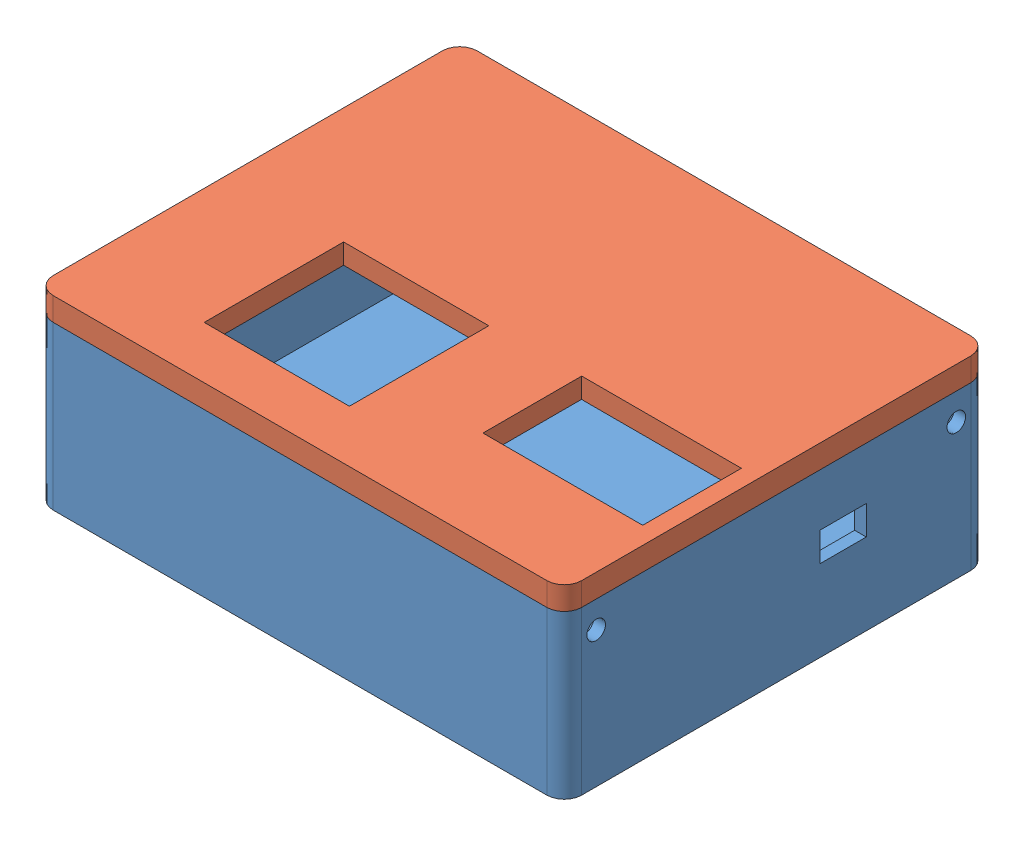
SolidWorks assembly 整体, configuration 默认. Lengths in mm.
Overall size (91 32 73).
2 component instances, 2 part files, 2 mates.
Components (placement in the parent):
- 外壳-1: 外壳 [默认] at (-8.2216 15.1622 0) size (91 28 73)
- 盖子-1: 盖子 [默认] at (-53.7216 43.1622 36.5) x (1 0 0) z (0 0 -1) size (91 11.51 73)
Mates (geometry in assembly coordinates):
- 重合1: coincident anti-aligned: line of 外壳-1 through (-50.7216 43.1622 36.5) axis (1 0 0); line of 盖子-1 through (34.2784 43.1622 36.5) axis (-1 0 0)
- 重合2: coincident anti-aligned: line of 外壳-1 through (-53.7216 43.1622 -33.5) axis (0 0 1); line of 盖子-1 through (-53.7216 43.1622 33.5) axis (0 0 -1)
